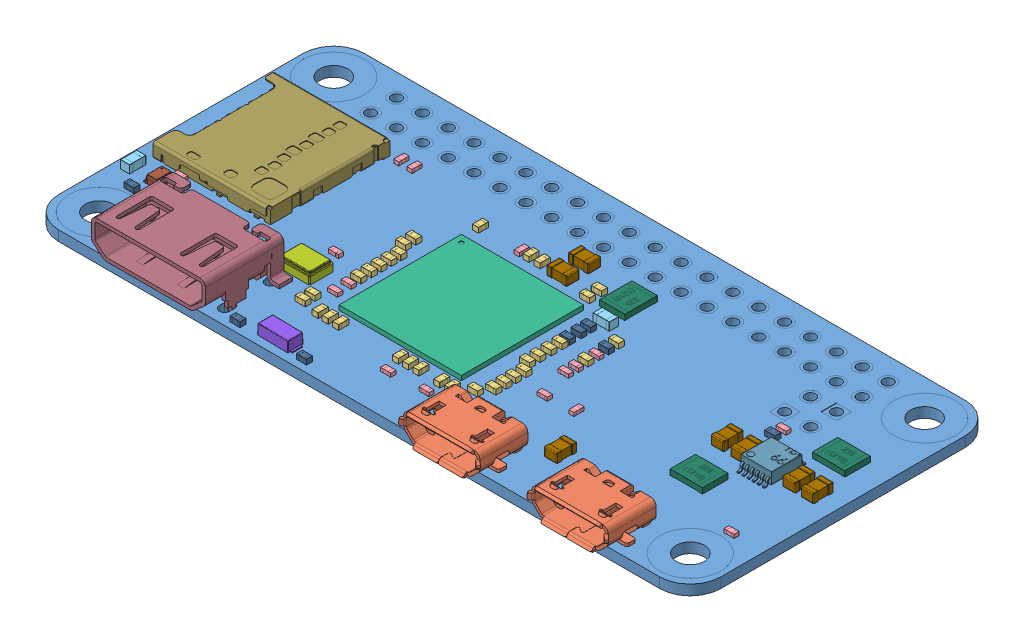
SolidWorks assembly RapberryPiZero, configuration Default. Lengths in mm.
Overall size (65 4.45 31.23).
81 component instances, 15 part files, 154 mates.
Components (placement in the parent):
- Raspberry_pizero_PCB-1: Raspberry_pizero_PCB [Default] at (-51.2564 20.0966 13.0542) size (65 1 30)
- Micro USB_input_female (short)-SMT-1: Micro USB_input_female (short)-SMT [Default] at (-42.3564 22.3216 26.5042) size (7.98 2.94 5.43)
- Micro USB_input_female (short)-SMT-2: Micro USB_input_female (short)-SMT [Default] at (-29.7564 22.3216 26.5042) size (7.98 2.94 5.43)
- 0204 - Capacitor-1: 0204 - Capacitor [Default] at (-62.4121 21.3466 11.2398) size (1 0.5 0.6)
- 0204 - Capacitor-2: 0204 - Capacitor [Default] at (-62.4121 21.3466 12.2528) size (1 0.5 0.6)
- 0204 - Capacitor-3: 0204 - Capacitor [Default] at (-61.8122 21.3466 13.3136) size (1 0.5 0.6)
- 0204 - Capacitor-4: 0204 - Capacitor [Default] at (-61.8122 21.3466 14.2646) size (1 0.5 0.6)
- 0204 - Capacitor-5: 0204 - Capacitor [Default] at (-61.8122 21.3466 15.241) size (1 0.5 0.6)
- 0204 - Capacitor-6: 0204 - Capacitor [Default] at (-61.8122 21.3466 16.2144) size (1 0.5 0.6)
- 0204 - Capacitor-7: 0204 - Capacitor [Default] at (-61.8122 21.3466 17.2416) size (1 0.5 0.6)
- 0204 - Capacitor-8: 0204 - Capacitor [Default] at (-62.5919 21.3466 20.9695) size (1 0.5 0.6)
- 0204 - Capacitor-9: 0204 - Capacitor [Default] at (-62.5919 21.3466 21.919) size (1 0.5 0.6)
- 0204 - Capacitor-10: 0204 - Capacitor [Default] at (-60.4584 21.3466 22.3712) x (0 0 1) z (-1 0 0) size (1 0.5 0.6)
- 0204 - Capacitor-11: 0204 - Capacitor [Default] at (-60.0807 21.3466 22.3712) x (0 0 -1) z (1 0 0) size (1 0.5 0.6)
- 0204 - Capacitor-12: 0204 - Capacitor [Default] at (-59.0466 21.3466 22.3712) x (0 0 -1) z (1 0 0) size (1 0.5 0.6)
- 0204 - Capacitor-13: 0204 - Capacitor [Default] at (-52.6496 21.3466 22.316) x (0 0 1) z (-1 0 0) size (1 0.5 0.6)
- 0204 - Capacitor-14: 0204 - Capacitor [Default] at (-52.25 21.3466 22.316) x (0 0 -1) z (1 0 0) size (1 0.5 0.6)
- 0204 - Capacitor-15: 0204 - Capacitor [Default] at (-51.2398 21.3466 22.316) x (0 0 -1) z (1 0 0) size (1 0.5 0.6)
- 0204 - Capacitor-16: 0204 - Capacitor [Default] at (-49.1841 21.3466 22.316) x (0 0 -1) z (1 0 0) size (1 0.5 0.6)
- 0204 - Capacitor-17: 0204 - Capacitor [Default] at (-48.1448 21.3466 22.316) x (0 0 -1) z (1 0 0) size (1 0.5 0.6)
- 0204 - Capacitor-18: 0204 - Capacitor [Default] at (-46.475 21.3466 21.113) size (1 0.5 0.6)
- 0204 - Capacitor-19: 0204 - Capacitor [Default] at (-45.7322 21.3466 20.0663) size (1 0.5 0.6)
- 0204 - Capacitor-20: 0204 - Capacitor [Default] at (-45.7322 21.3466 19.0675) size (1 0.5 0.6)
- 0204 - Capacitor-21: 0204 - Capacitor [Default] at (-45.7322 21.3466 18.1249) size (1 0.5 0.6)
- 0204 - Capacitor-22: 0204 - Capacitor [Default] at (-45.7322 21.3466 17.1095) size (1 0.5 0.6)
- 0204 - Capacitor-23: 0204 - Capacitor [Default] at (-46.3457 21.3466 16.1412) size (1 0.5 0.6)
- 0204 - Capacitor-24: 0204 - Capacitor [Default] at (-46.3457 21.3466 15.1229) size (1 0.5 0.6)
- 0204 - Capacitor-25: 0204 - Capacitor [Default] at (-46.3457 21.3466 14.0197) size (1 0.5 0.6)
- 0204 - Capacitor-26: 0204 - Capacitor [Default] at (-46.3457 21.3466 12.9589) size (1 0.5 0.6)
- 0204 - Capacitor-27: 0204 - Capacitor [Default] at (-43.6156 21.3466 13.1418) size (1 0.5 0.6)
- 0204 - Capacitor-28: 0204 - Capacitor [Default] at (-43.6156 21.3466 10.1424) size (1 0.5 0.6)
- 0204 - Capacitor-29: 0204 - Capacitor [Default] at (-48.9117 21.3466 7.6917) size (1 0.5 0.6)
- 0204 - Capacitor-30: 0204 - Capacitor [Default] at (-55.4926 21.3466 7.2526) x (0 0 -1) z (1 0 0) size (1 0.5 0.6)
- 0204 - Capacitor-31: 0204 - Capacitor [Default] at (-53.7932 21.3466 7.2526) x (0 0 1) z (-1 0 0) size (1 0.5 0.6)
- 0204 - Capacitor-32: 0204 - Capacitor [Default] at (-59.8477 21.3466 7.2526) x (0 0 1) z (-1 0 0) size (1 0.5 0.6)
- 0204- Resistor-15: 0204- Resistor [Default] at (-43.6109 21.4522 15.4193) x (-1 0 0) z (0 -1 0) size (0.99 0.51 0.36)
- 0204- Resistor-14: 0204- Resistor [Default] at (-43.6109 21.4522 14.4127) x (-1 0 0) z (0 -1 0) size (0.99 0.51 0.36)
- 0204- Resistor-13: 0204- Resistor [Default] at (-43.6109 21.4522 12.4047) x (-1 0 0) z (0 -1 0) size (0.99 0.51 0.36)
- 0204- Resistor-4: 0204- Resistor [Default] at (-42.6936 21.4522 18.4076) x (-1 0 0) z (0 -1 0) size (0.99 0.51 0.36)
- 0204- Resistor-5: 0204- Resistor [Default] at (-39.831 21.4522 18.1462) x (0 0 1) z (0 -1 0) size (0.99 0.51 0.36)
- 0204- Resistor-7: 0204- Resistor [Default] at (-61.8169 21.4522 19.8533) x (-1 0 0) z (0 -1 0) size (0.99 0.51 0.36)
- 0204- Resistor-8: 0204- Resistor [Default] at (-61.8169 21.4522 18.5178) x (-1 0 0) z (0 -1 0) size (0.99 0.51 0.36)
- 0204- Resistor-9: 0204- Resistor [Default] at (-79.148 21.4522 17.7279) x (-1 0 0) z (0 -1 0) size (0.99 0.51 0.36)
- 0204- Resistor-10: 0204- Resistor [Default] at (-56.0985 21.4522 7.2479) x (0 0 -1) z (0 -1 0) size (0.99 0.51 0.36)
- 0204- Resistor-11: 0204- Resistor [Default] at (-28.0827 21.4522 9.5819) x (-1 0 0) z (0 -1 0) size (0.99 0.51 0.36)
- 0204- Resistor-12: 0204- Resistor [Default] at (-21.8613 21.4522 20.9026) x (-1 0 0) z (0 -1 0) size (0.99 0.51 0.36)
- CAP-0306-1: CAP-0306 [Default] at (-45.8903 21.4966 8.7634) size (1.6 0.8 0.9)
- CAP-0306-2: CAP-0306 [Default] at (-82.0031 21.4966 19.0464) x (0 0 1) z (-1 0 0) size (1.6 0.8 0.9)
- Raspberry_pizero_BCM2835 with VC4-2: Raspberry_pizero_BCM2835 with VC4 [Default] at (-54.1608 21.5466 15.1238) x (1 0 0) z (0 0 -1) size (12 0.65 12)
- Crystal 3.4x2.4mm-1: Crystal 3.4x2.4mm [Default] at (-65.3089 21.0966 19.2633) size (3.2 1 2.4)
- 0204- Resistor-16: 0204- Resistor [Default] at (-68.4329 21.4522 5.4384) x (0 0 1) z (0 -1 0) size (0.99 0.51 0.36)
- 0204- Resistor-17: 0204- Resistor [Default] at (-69.7255 21.4522 5.4384) x (0 0 1) z (0 -1 0) size (0.99 0.51 0.36)
- 0204- Resistor-18: 0204- Resistor [Default] at (-65.0626 21.4522 16.5355) x (1 0 0) z (0 -1 0) size (0.99 0.51 0.36)
- 32,768 Khz Crystal-1: 32,768 Khz Crystal [Default] at (-60.5154 21.1428 26.5473) x (0.999848 -0.017452 0) z (0 0 1) size (3.4 1.03 1.5)
- 0805- Capacitor-1: 0805- Capacitor [Default] at (-51.9496 21.9966 5.2384) x (1 0 0) z (0 -1 0) size (2 1.25 0.9)
- 0805- Capacitor-2: 0805- Capacitor [Default] at (-51.9496 21.9966 7.3589) x (1 0 0) z (0 -1 0) size (2 1.25 0.9)
- 0805- Capacitor-3: 0805- Capacitor [Default] at (-37.009 21.9966 22.5384) x (0 0 -1) z (0 -1 0) size (2 1.25 0.9)
- 0805- Capacitor-4: 0805- Capacitor [Default] at (-29.8247 21.9966 13.3538) x (0 0 1) z (0 -1 0) size (2 1.25 0.9)
- 0805- Capacitor-5: 0805- Capacitor [Default] at (-27.9052 21.9966 13.3538) x (0 0 -1) z (0 -1 0) size (2 1.25 0.9)
- 0805- Capacitor-6: 0805- Capacitor [Default] at (-22.8003 21.9966 13.3538) x (0 0 -1) z (0 -1 0) size (2 1.25 0.9)
- 0805- Capacitor-7: 0805- Capacitor [Default] at (-20.9924 21.9966 13.3538) x (0 0 -1) z (0 -1 0) size (2 1.25 0.9)
- 0204- Resistor-19: 0204- Resistor [Default] at (-48.8769 21.4522 23.8207) x (1 0 0) z (0 -1 0) size (0.99 0.51 0.36)
- 0204- Resistor-20: 0204- Resistor [Default] at (-52.4165 21.4522 24.0419) x (1 0 0) z (0 -1 0) size (0.99 0.51 0.36)
- 0204 - Capacitor-33: 0204 - Capacitor [Default] at (-47.1199 21.3466 23.926) x (0 0 1) z (-1 0 0) size (1 0.5 0.6)
- 0204 - Capacitor Brown-34: 0204 - Capacitor Brown [Default] at (-57.5817 21.3466 26.803) size (1 0.5 0.6)
- 0204 - Capacitor Brown-35: 0204 - Capacitor Brown [Default] at (-64.0312 21.3466 26.8794) size (1 0.5 0.6)
- 0204 - Capacitor Brown-36: 0204 - Capacitor Brown [Default] at (-46.3457 21.3466 12.214) size (1 0.5 0.6)
- 0204 - Capacitor Brown-37: 0204 - Capacitor Brown [Default] at (-46.3457 21.3466 11.0963) size (1 0.5 0.6)
- 0204 - Capacitor Brown-38: 0204 - Capacitor Brown [Default] at (-46.3457 21.3466 10.1566) size (1 0.5 0.6)
- 0204 - Capacitor Brown-39: 0204 - Capacitor Brown [Default] at (-43.6156 21.3466 11.1151) size (1 0.5 0.6)
- 0204 - Capacitor Brown-40: 0204 - Capacitor Brown [Default] at (-28.0874 21.3466 10.3236) size (1 0.5 0.6)
- 0204 - Capacitor Brown-41: 0204 - Capacitor Brown [Default] at (-80.6197 21.3466 20.6997) size (1 0.5 0.6)
- 0204- Resistor-21: 0204- Resistor [Default] at (-78.9105 21.4522 21.1554) x (1 0 0) z (0 -1 0) size (0.99 0.51 0.36)
- 6-Pin SOT-1: 6-Pin SOT [Default] at (-79.714 21.0966 19.2138) x (0 0 1) z (0 1 0) size (1.5 1.84 0.95)
- micro sd molex-1: micro sd molex [Default] at (-74.7768 21.6766 -33.0961) x (0 0 1) z (0 1 0) size (11.95 11.4 1.45)
- hdmi type C-1: hdmi type C [Default] at (-71.3564 22.9466 28.6542) size (12.9 4.05 7.7)
- Voltage Regulator 3x3mm 12-Pin-1: Voltage Regulator 3x3mm 12-Pin [Default] at (-23.6842 21.0966 12.6105) x (1 0 0) z (0 1 0) size (3 4.1 1.2)
- 1210 inductor-1: 1210 inductor [Default] at (-46.4963 21.0916 6.3909) x (0 0 1) z (0 1 0) size (3.26 2.86 0.75)
- 1210 inductor-2: 1210 inductor [Default] at (-22.7405 21.0916 9.2394) x (1 0 0) z (0 1 0) size (3.26 2.86 0.75)
- 1210 inductor-3: 1210 inductor [Default] at (-28.2854 21.0916 17.6682) x (1 0 0) z (0 1 0) size (3.26 2.86 0.75)
- 0204 - Capacitor-34: 0204 - Capacitor [Default] at (-48.9117 21.3466 6.5273) size (1 0.5 0.6)
Mates (geometry in assembly coordinates):
- Coincident1: coincident anti-aligned: plane of Raspberry_pizero_PCB-1 through (-80.7564 21.0966 1.0542) normal (0 1 0); plane of Micro USB_input_female (short)-SMT-1 through (-46.4124 21.0966 24.1966) normal (0 -1 0)
- Coincident2: coincident anti-aligned: plane of Raspberry_pizero_PCB-1 through (-80.7564 21.0966 1.0542) normal (0 1 0); plane of Micro USB_input_female (short)-SMT-2 through (-33.8124 21.0966 24.1966) normal (0 -1 0)
- Coincident3: coincident aligned: plane of 0204 - Capacitor-13 through (-52.9516 21.5916 22.316) normal (0 1 0); plane of 0204 - Capacitor-14 through (-51.948 21.5916 22.316) normal (0 1 0)
- Coincident4: coincident aligned: plane of 0204 - Capacitor-14 through (-51.948 21.5916 22.316) normal (0 1 0); plane of 0204 - Capacitor-15 through (-50.9378 21.5916 22.316) normal (0 1 0)
- Coincident5: coincident aligned: plane of 0204 - Capacitor-15 through (-50.9378 21.5916 22.316) normal (0 1 0); plane of 0204 - Capacitor-16 through (-48.8821 21.5916 22.316) normal (0 1 0)
- Coincident6: coincident aligned: plane of 0204 - Capacitor-16 through (-48.8821 21.5916 22.316) normal (0 1 0); plane of 0204 - Capacitor-17 through (-47.8428 21.5916 22.316) normal (0 1 0)
- Coincident7: coincident aligned: plane of 0204 - Capacitor-17 through (-47.8428 21.5916 22.316) normal (0 1 0); plane of 0204 - Capacitor-18 through (-46.475 21.5916 21.415) normal (0 1 0)
- Coincident8: coincident aligned: plane of 0204 - Capacitor-18 through (-46.475 21.5916 21.415) normal (0 1 0); plane of 0204 - Capacitor-19 through (-45.7322 21.5916 20.3683) normal (0 1 0)
- Coincident9: coincident aligned: plane of 0204 - Capacitor-19 through (-45.7322 21.5916 20.3683) normal (0 1 0); plane of 0204 - Capacitor-20 through (-45.7322 21.5916 19.3695) normal (0 1 0)
- Coincident10: coincident aligned: plane of 0204 - Capacitor-20 through (-45.7322 21.5916 19.3695) normal (0 1 0); plane of 0204 - Capacitor-21 through (-45.7322 21.5916 18.4269) normal (0 1 0)
- Coincident11: coincident aligned: plane of 0204 - Capacitor-21 through (-45.7322 21.5916 18.4269) normal (0 1 0); plane of 0204 - Capacitor-22 through (-45.7322 21.5916 17.4115) normal (0 1 0)
- Coincident12: coincident aligned: plane of 0204 - Capacitor-22 through (-45.7322 21.5916 17.4115) normal (0 1 0); plane of 0204 - Capacitor-23 through (-46.3457 21.5916 16.4432) normal (0 1 0)
- Coincident13: coincident aligned: plane of 0204 - Capacitor-23 through (-46.3457 21.5916 16.4432) normal (0 1 0); plane of 0204 - Capacitor-24 through (-46.3457 21.5916 15.4249) normal (0 1 0)
- Coincident14: coincident aligned: plane of 0204 - Capacitor-24 through (-46.3457 21.5916 15.4249) normal (0 1 0); plane of 0204 - Capacitor-25 through (-46.3457 21.5916 14.3217) normal (0 1 0)
- Coincident15: coincident aligned: plane of 0204 - Capacitor-25 through (-46.3457 21.5916 14.3217) normal (0 1 0); plane of 0204 - Capacitor-26 through (-46.3457 21.5916 13.2609) normal (0 1 0)
- Coincident16: coincident aligned: plane of 0204 - Capacitor-26 through (-46.3457 21.5916 13.2609) normal (0 1 0); plane of 0204 - Capacitor-27 through (-43.6156 21.5916 13.4438) normal (0 1 0)
- Coincident17: coincident aligned: plane of 0204 - Capacitor-27 through (-43.6156 21.5916 13.4438) normal (0 1 0); plane of 0204 - Capacitor-28 through (-43.6156 21.5916 10.4444) normal (0 1 0)
- Coincident18: coincident aligned: plane of 0204 - Capacitor-28 through (-43.6156 21.5916 10.4444) normal (0 1 0); plane of 0204 - Capacitor-29 through (-48.9117 21.5916 7.9937) normal (0 1 0)
- Coincident19: coincident aligned: plane of 0204 - Capacitor-29 through (-48.9117 21.5916 7.9937) normal (0 1 0); plane of 0204 - Capacitor-31 through (-54.0952 21.5916 7.2526) normal (0 1 0)
- Coincident20: coincident aligned: plane of 0204 - Capacitor-30 through (-55.1906 21.5916 7.2526) normal (0 1 0); plane of 0204 - Capacitor-31 through (-54.0952 21.5916 7.2526) normal (0 1 0)
- Coincident21: coincident aligned: plane of 0204 - Capacitor-30 through (-55.1906 21.5916 7.2526) normal (0 1 0); plane of 0204 - Capacitor-32 through (-60.1497 21.5916 7.2526) normal (0 1 0)
- Coincident22: coincident aligned: plane of 0204 - Capacitor-1 through (-62.4121 21.5916 11.5418) normal (0 1 0); plane of 0204 - Capacitor-32 through (-60.1497 21.5916 7.2526) normal (0 1 0)
- Coincident23: coincident aligned: plane of 0204 - Capacitor-1 through (-62.4121 21.5916 11.5418) normal (0 1 0); plane of 0204 - Capacitor-2 through (-62.4121 21.5916 12.5548) normal (0 1 0)
- Coincident24: coincident aligned: plane of 0204 - Capacitor-2 through (-62.4121 21.5916 12.5548) normal (0 1 0); plane of 0204 - Capacitor-3 through (-61.8122 21.5916 13.6156) normal (0 1 0)
- Coincident25: coincident aligned: plane of 0204 - Capacitor-3 through (-61.8122 21.5916 13.6156) normal (0 1 0); plane of 0204 - Capacitor-4 through (-61.8122 21.5916 14.5666) normal (0 1 0)
- Coincident26: coincident aligned: plane of 0204 - Capacitor-4 through (-61.8122 21.5916 14.5666) normal (0 1 0); plane of 0204 - Capacitor-5 through (-61.8122 21.5916 15.543) normal (0 1 0)
- Coincident27: coincident aligned: plane of 0204 - Capacitor-5 through (-61.8122 21.5916 15.543) normal (0 1 0); plane of 0204 - Capacitor-6 through (-61.8122 21.5916 16.5164) normal (0 1 0)
- Coincident28: coincident aligned: plane of 0204 - Capacitor-6 through (-61.8122 21.5916 16.5164) normal (0 1 0); plane of 0204 - Capacitor-7 through (-61.8122 21.5916 17.5436) normal (0 1 0)
- Coincident29: coincident aligned: plane of 0204 - Capacitor-7 through (-61.8122 21.5916 17.5436) normal (0 1 0); plane of 0204 - Capacitor-8 through (-62.5919 21.5916 21.2715) normal (0 1 0)
- Coincident30: coincident aligned: plane of 0204 - Capacitor-8 through (-62.5919 21.5916 21.2715) normal (0 1 0); plane of 0204 - Capacitor-9 through (-62.5919 21.5916 22.221) normal (0 1 0)
- Coincident31: coincident aligned: plane of 0204 - Capacitor-9 through (-62.5919 21.5916 22.221) normal (0 1 0); plane of 0204 - Capacitor-10 through (-60.7604 21.5916 22.3712) normal (0 1 0)
- Coincident32: coincident aligned: plane of 0204 - Capacitor-10 through (-60.7604 21.5916 22.3712) normal (0 1 0); plane of 0204 - Capacitor-11 through (-59.7787 21.5916 22.3712) normal (0 1 0)
- Coincident33: coincident aligned: plane of 0204 - Capacitor-11 through (-59.7787 21.5916 22.3712) normal (0 1 0); plane of 0204 - Capacitor-12 through (-58.7446 21.5916 22.3712) normal (0 1 0)
- Coincident34: coincident anti-aligned: plane of Raspberry_pizero_PCB-1 through (-80.7564 21.0966 1.0542) normal (0 1 0); plane of 0204 - Capacitor-9 through (-62.9669 21.0966 22.219) normal (0 -1 0)
- Coincident35: coincident aligned: plane of 0204 - Capacitor-25 through (-46.8457 21.0966 14.3197) normal (-1 0 0); plane of 0204 - Capacitor-26 through (-46.8457 21.0966 13.2589) normal (-1 0 0)
- Coincident36: coincident aligned: plane of 0204 - Capacitor-24 through (-46.8457 21.0966 15.4229) normal (-1 0 0); plane of 0204 - Capacitor-25 through (-46.8457 21.0966 14.3197) normal (-1 0 0)
- Coincident37: coincident aligned: plane of 0204 - Capacitor-23 through (-46.8457 21.0966 16.4412) normal (-1 0 0); plane of 0204 - Capacitor-24 through (-46.8457 21.0966 15.4229) normal (-1 0 0)
- Coincident38: coincident aligned: plane of 0204 - Capacitor-27 through (-44.1156 21.0966 13.4418) normal (-1 0 0); plane of 0204 - Capacitor-28 through (-44.1156 21.0966 10.4424) normal (-1 0 0)
- Parallel1: parallel anti-aligned: plane of Raspberry_pizero_PCB-1 through (-80.7564 21.0966 -1.9458) normal (0 0 -1); plane of 0204 - Capacitor-30 through (-55.1926 21.0966 7.7526) normal (0 0 1)
- Coincident39: coincident aligned: plane of 0204 - Capacitor-30 through (-55.1926 21.0966 6.7526) normal (0 0 -1); plane of 0204 - Capacitor-31 through (-54.0932 21.0966 6.7526) normal (0 0 -1)
- Coincident40: coincident aligned: plane of 0204 - Capacitor-30 through (-55.1926 21.0966 6.7526) normal (0 0 -1); plane of 0204 - Capacitor-32 through (-60.1477 21.0966 6.7526) normal (0 0 -1)
- Coincident41: coincident aligned: plane of 0204 - Capacitor-1 through (-62.9121 21.0966 11.5398) normal (-1 0 0); plane of 0204 - Capacitor-2 through (-62.9121 21.0966 12.5528) normal (-1 0 0)
- Coincident42: coincident aligned: plane of 0204 - Capacitor-3 through (-62.3122 21.0966 13.6136) normal (-1 0 0); plane of 0204 - Capacitor-4 through (-62.3122 21.0966 14.5646) normal (-1 0 0)
- Coincident43: coincident aligned: plane of 0204 - Capacitor-4 through (-62.3122 21.0966 14.5646) normal (-1 0 0); plane of 0204 - Capacitor-5 through (-62.3122 21.0966 15.541) normal (-1 0 0)
- Coincident44: coincident aligned: plane of 0204 - Capacitor-5 through (-62.3122 21.0966 15.541) normal (-1 0 0); plane of 0204 - Capacitor-6 through (-62.3122 21.0966 16.5144) normal (-1 0 0)
- Coincident45: coincident aligned: plane of 0204 - Capacitor-6 through (-62.3122 21.0966 16.5144) normal (-1 0 0); plane of 0204 - Capacitor-7 through (-62.3122 21.0966 17.5416) normal (-1 0 0)
- Coincident46: coincident aligned: plane of 0204 - Capacitor-8 through (-63.0919 21.0966 21.2695) normal (-1 0 0); plane of 0204 - Capacitor-9 through (-63.0919 21.0966 22.219) normal (-1 0 0)
- Parallel2: parallel anti-aligned: plane of Raspberry_pizero_PCB-1 through (-80.7564 21.0966 28.0542) normal (0 0 1); plane of 0204 - Capacitor-10 through (-60.7584 21.0966 21.8712) normal (0 0 -1)
- Coincident48: coincident aligned: plane of 0204 - Capacitor-10 through (-60.7584 21.0966 22.8712) normal (0 0 1); plane of 0204 - Capacitor-11 through (-59.7807 21.0966 22.8712) normal (0 0 1)
- Coincident49: coincident aligned: plane of 0204 - Capacitor-11 through (-59.7807 21.0966 22.8712) normal (0 0 1); plane of 0204 - Capacitor-12 through (-58.7466 21.0966 22.8712) normal (0 0 1)
- Parallel3: parallel anti-aligned: plane of Raspberry_pizero_PCB-1 through (-80.7564 21.0966 28.0542) normal (0 0 1); plane of 0204 - Capacitor-13 through (-52.9496 21.0966 21.816) normal (0 0 -1)
- Coincident51: coincident aligned: plane of 0204 - Capacitor-13 through (-52.9496 21.0966 22.816) normal (0 0 1); plane of 0204 - Capacitor-14 through (-51.95 21.0966 22.816) normal (0 0 1)
- Coincident52: coincident aligned: plane of 0204 - Capacitor-14 through (-51.95 21.0966 22.816) normal (0 0 1); plane of 0204 - Capacitor-15 through (-50.9398 21.0966 22.816) normal (0 0 1)
- Coincident53: coincident aligned: plane of 0204 - Capacitor-15 through (-50.9398 21.0966 22.816) normal (0 0 1); plane of 0204 - Capacitor-16 through (-48.8841 21.0966 22.816) normal (0 0 1)
- Coincident54: coincident aligned: plane of 0204 - Capacitor-16 through (-48.8841 21.0966 22.816) normal (0 0 1); plane of 0204 - Capacitor-17 through (-47.8448 21.0966 22.816) normal (0 0 1)
- Parallel7: parallel anti-aligned: plane of Raspberry_pizero_PCB-1 through (-80.7564 21.0966 28.0542) normal (0 0 1); plane of CAP-0306-2 through (-82.4531 21.0966 18.2464) normal (0 0 -1)
- Parallel8: parallel aligned: plane of Raspberry_pizero_PCB-1 through (-18.7564 21.0966 25.0542) normal (1 0 0); plane of CAP-0306-1 through (-45.0903 21.0966 9.2134) normal (1 0 0)
- Coincident77: coincident aligned: plane of 0204 - Capacitor-21 through (-46.2322 21.0966 18.4249) normal (-1 0 0); plane of 0204 - Capacitor-22 through (-46.2322 21.0966 17.4095) normal (-1 0 0)
- Coincident78: coincident aligned: plane of 0204 - Capacitor-20 through (-46.2322 21.0966 19.3675) normal (-1 0 0); plane of 0204 - Capacitor-21 through (-46.2322 21.0966 18.4249) normal (-1 0 0)
- Coincident79: coincident aligned: plane of 0204 - Capacitor-19 through (-46.2322 21.0966 20.3663) normal (-1 0 0); plane of 0204 - Capacitor-20 through (-46.2322 21.0966 19.3675) normal (-1 0 0)
- Coincident80: coincident aligned: plane of Micro USB_input_female (short)-SMT-1 through (-39.2364 21.3596 23.1542) normal (0 0 -1); plane of Micro USB_input_female (short)-SMT-2 through (-26.6364 21.3596 23.1542) normal (0 0 -1)
- Distance1: distance = 41.4 mm: moEndPointRef_w of Micro USB_input_female (short)-SMT-1; plane of Raspberry_pizero_PCB-1 through (-83.7564 21.0966 25.0542) normal (-1 0 0)
- Distance3: distance = 0.8 mm aligned: plane of Micro USB_input_female (short)-SMT-1 through (-46.2564 21.0476 28.8542) normal (0 0 1); plane of Raspberry_pizero_PCB-1 through (-80.7564 21.0966 28.0542) normal (0 0 1)
- Distance4: distance = 54 mm: moEndPointRef_w of Micro USB_input_female (short)-SMT-2; plane of Raspberry_pizero_PCB-1 through (-83.7564 21.0966 25.0542) normal (-1 0 0)
- Coincident86: coincident anti-aligned: plane of Raspberry_pizero_PCB-1 through (-80.7564 21.0966 1.0542) normal (0 1 0); plane of Raspberry_pizero_BCM2835 with VC4-2 through (-54.1608 21.0966 15.1238) normal (0 -1 0)
- Parallel10: parallel anti-aligned: plane of Raspberry_pizero_BCM2835 with VC4-2 through (-60.1608 21.0966 9.1238) normal (0 0 -1); plane of Raspberry_pizero_PCB-1 through (-80.7564 21.0966 28.0542) normal (0 0 1)
- Coincident88: coincident anti-aligned: plane of Raspberry_pizero_PCB-1 through (-80.7564 21.0966 1.0542) normal (0 1 0); plane of CAP-0306-1 through (-45.2653 21.0966 9.2134) normal (0 -1 0)
- Coincident89: coincident aligned: plane of 0204- Resistor-7 through (-61.5248 21.0966 19.5993) normal (0 -1 0); plane of 0204- Resistor-8 through (-61.5248 21.0966 18.2638) normal (0 -1 0)
- Coincident90: coincident anti-aligned: plane of Raspberry_pizero_PCB-1 through (-80.7564 21.0966 1.0542) normal (0 1 0); plane of 0204- Resistor-8 through (-61.5248 21.0966 18.2638) normal (0 -1 0)
- Parallel11: parallel aligned: plane of Raspberry_pizero_PCB-1 through (-80.7564 21.0966 28.0542) normal (0 0 1); plane of 0204 - Capacitor-7 through (-61.8122 21.1016 17.8406) normal (0 0 1)
- Coincident92: coincident aligned: plane of 0204 - Capacitor-7 through (-62.3122 21.0966 17.5416) normal (-1 0 0); plane of 0204- Resistor-8 through (-62.3122 21.0966 18.2638) normal (-1 0 0)
- Coincident93: coincident aligned: plane of 0204- Resistor-7 through (-62.3122 21.0966 19.5993) normal (-1 0 0); plane of 0204- Resistor-8 through (-62.3122 21.0966 18.2638) normal (-1 0 0)
- Coincident94: coincident aligned: plane of 0204 - Capacitor-30 through (-55.1926 21.0966 6.7526) normal (0 0 -1); plane of 0204- Resistor-10 through (-55.8445 21.0966 6.7526) normal (0 0 -1)
- Coincident95: coincident anti-aligned: plane of Raspberry_pizero_PCB-1 through (-80.7564 21.0966 1.0542) normal (0 1 0); plane of 0204- Resistor-10 through (-55.8445 21.0966 6.9558) normal (0 -1 0)
- Coincident96: coincident aligned: plane of 0204- Resistor-14 through (-43.903 21.0966 14.1587) normal (0 -1 0); plane of 0204- Resistor-13 through (-43.903 21.0966 12.1507) normal (0 -1 0)
- Coincident97: coincident aligned: plane of 0204- Resistor-15 through (-43.903 21.0966 15.1653) normal (0 -1 0); plane of 0204- Resistor-14 through (-43.903 21.0966 14.1587) normal (0 -1 0)
- Coincident98: coincident aligned: plane of 0204- Resistor-15 through (-43.903 21.0966 15.1653) normal (0 -1 0); plane of 0204- Resistor-4 through (-42.9857 21.0966 18.1536) normal (0 -1 0)
- Coincident99: coincident anti-aligned: plane of Raspberry_pizero_PCB-1 through (-80.7564 21.0966 1.0542) normal (0 1 0); plane of 0204- Resistor-15 through (-43.903 21.0966 15.1653) normal (0 -1 0)
- Coincident101: coincident aligned: plane of 0204- Resistor-5 through (-40.085 21.0966 18.4383) normal (0 -1 0); plane of 0204- Resistor-11 through (-27.7906 21.0966 9.3279) normal (0 -1 0)
- Coincident102: coincident aligned: plane of 0204- Resistor-11 through (-27.7906 21.0966 9.3279) normal (0 -1 0); plane of 0204- Resistor-12 through (-21.5692 21.0966 20.6486) normal (0 -1 0)
- Coincident103: coincident anti-aligned: plane of Raspberry_pizero_PCB-1 through (-80.7564 21.0966 1.0542) normal (0 1 0); plane of Crystal 3.4x2.4mm-1 through (-65.3089 21.0966 19.2633) normal (0 -1 0)
- Parallel12: parallel aligned: plane of Raspberry_pizero_PCB-1 through (-80.7564 21.0966 28.0542) normal (0 0 1); plane of Crystal 3.4x2.4mm-1 through (-66.9089 21.7966 20.4633) normal (0 0 1)
- Coincident104: coincident anti-aligned: plane of Raspberry_pizero_PCB-1 through (-80.7564 21.0966 1.0542) normal (0 1 0); plane of 0204- Resistor-9 through (-78.8559 21.0966 17.4739) normal (0 -1 0)
- Parallel13: parallel aligned: plane of Raspberry_pizero_PCB-1 through (-80.7564 21.0966 28.0542) normal (0 0 1); plane of 0204- Resistor-9 through (-78.2985 21.4532 17.9829) normal (0 0 1)
- Coincident105: coincident anti-aligned: plane of Raspberry_pizero_PCB-1 through (-80.7564 21.0966 1.0542) normal (0 1 0); plane of CAP-0306-2 through (-82.4531 21.0966 19.6714) normal (0 -1 0)
- Coincident106: coincident aligned: plane of 0204 - Capacitor-28 through (-43.1156 21.0966 10.4424) normal (1 0 0); plane of 0204- Resistor-13 through (-43.1156 21.0966 12.1507) normal (1 0 0)
- Coincident107: coincident aligned: plane of 0204 - Capacitor-27 through (-43.1156 21.0966 13.4418) normal (1 0 0); plane of 0204- Resistor-14 through (-43.1156 21.0966 14.1587) normal (1 0 0)
- Parallel14: parallel aligned: plane of Raspberry_pizero_PCB-1 through (-80.7564 21.0966 28.0542) normal (0 0 1); plane of 0204- Resistor-14 through (-42.7614 21.4532 14.6677) normal (0 0 1)
- Coincident110: coincident aligned: plane of 0204- Resistor-15 through (-43.1156 21.0966 15.1653) normal (1 0 0); plane of 0204- Resistor-14 through (-43.1156 21.0966 14.1587) normal (1 0 0)
- Parallel15: parallel aligned: plane of 0204- Resistor-15 through (-43.1156 21.0966 15.1653) normal (1 0 0); plane of 0204- Resistor-4 through (-42.1983 21.0966 18.1536) normal (1 0 0)
- Parallel16: parallel aligned: plane of Raspberry_pizero_PCB-1 through (-80.7564 21.0966 28.0542) normal (0 0 1); plane of 0204- Resistor-5 through (-40.085 21.0966 18.6415) normal (0 0 1)
- Coincident112: coincident anti-aligned: plane of Raspberry_pizero_PCB-1 through (-80.7564 21.0966 1.0542) normal (0 1 0); plane of 0204- Resistor-5 through (-40.085 21.0966 18.4383) normal (0 -1 0)
- Parallel17: parallel aligned: plane of Raspberry_pizero_PCB-1 through (-18.7564 21.0966 25.0542) normal (1 0 0); plane of 0204- Resistor-12 through (-21.366 21.0966 20.6486) normal (1 0 0)
- Parallel18: parallel aligned: plane of 0204- Resistor-11 through (-27.5874 21.0966 9.3279) normal (1 0 0); plane of 0204- Resistor-12 through (-21.366 21.0966 20.6486) normal (1 0 0)
- Coincident115: coincident anti-aligned: plane of Raspberry_pizero_PCB-1 through (-80.7564 21.0966 1.0542) normal (0 1 0); plane of 0204- Resistor-16 through (-68.6869 21.0966 5.1463) normal (0 -1 0)
- Coincident116: coincident aligned: plane of 0204- Resistor-16 through (-68.6879 21.4532 4.5889) normal (0 1 0); plane of 0204- Resistor-17 through (-69.9805 21.4532 4.5889) normal (0 1 0)
- Coincident117: coincident aligned: plane of 0204- Resistor-17 through (-69.9805 21.4532 4.5889) normal (0 1 0); plane of 0204- Resistor-18 through (-65.9121 21.4532 16.7905) normal (0 1 0)
- Coincident118: coincident aligned: plane of 0204- Resistor-16 through (-68.6869 21.0966 5.9337) normal (0 0 1); plane of 0204- Resistor-17 through (-69.9795 21.0966 5.9337) normal (0 0 1)
- Parallel19: parallel anti-aligned: plane of Raspberry_pizero_PCB-1 through (-80.7564 21.0966 -1.9458) normal (0 0 -1); plane of 0204- Resistor-17 through (-69.9795 21.0966 5.9337) normal (0 0 1)
- Parallel20: parallel aligned: plane of Raspberry_pizero_PCB-1 through (-80.7564 21.0966 28.0542) normal (0 0 1); plane of 0204- Resistor-18 through (-65.9121 21.4532 16.7905) normal (0 0 1)
- Coincident120: coincident anti-aligned: plane of Raspberry_pizero_PCB-1 through (-80.7564 21.0966 1.0542) normal (0 1 0); plane of 32,768 Khz Crystal-1 through (-59.5156 21.0966 27.0473) normal (0 -1 0)
- Coincident121: coincident anti-aligned: plane of Raspberry_pizero_PCB-1 through (-80.7564 21.0966 1.0542) normal (0 1 0); plane of 0805- Capacitor-1 through (-52.9496 21.0966 5.8634) normal (0 -1 0)
- Coincident122: coincident anti-aligned: plane of Raspberry_pizero_PCB-1 through (-80.7564 21.0966 1.0542) normal (0 1 0); plane of 0805- Capacitor-2 through (-52.9496 21.0966 7.9839) normal (0 -1 0)
- Coincident123: coincident anti-aligned: plane of Raspberry_pizero_PCB-1 through (-80.7564 21.0966 1.0542) normal (0 1 0); plane of 0805- Capacitor-3 through (-37.634 21.0966 21.5384) normal (0 -1 0)
- Coincident124: coincident anti-aligned: plane of Raspberry_pizero_PCB-1 through (-80.7564 21.0966 1.0542) normal (0 1 0); plane of 0805- Capacitor-4 through (-30.4497 21.0966 12.3538) normal (0 -1 0)
- Coincident125: coincident anti-aligned: plane of Raspberry_pizero_PCB-1 through (-80.7564 21.0966 1.0542) normal (0 1 0); plane of 0805- Capacitor-5 through (-27.2802 21.0966 14.3538) normal (0 -1 0)
- Parallel21: parallel anti-aligned: plane of Raspberry_pizero_PCB-1 through (-80.7564 21.0966 28.0542) normal (0 0 1); plane of 0805- Capacitor-4 through (-29.8247 21.9966 12.3538) normal (0 0 -1)
- Coincident126: coincident aligned: plane of 0805- Capacitor-4 through (-29.8247 21.9966 14.3538) normal (0 0 1); plane of 0805- Capacitor-5 through (-27.9052 21.9966 14.3538) normal (0 0 1)
- Coincident127: coincident anti-aligned: plane of Raspberry_pizero_PCB-1 through (-80.7564 21.0966 1.0542) normal (0 1 0); plane of 0805- Capacitor-6 through (-22.1753 21.0966 14.3538) normal (0 -1 0)
- Coincident128: coincident anti-aligned: plane of Raspberry_pizero_PCB-1 through (-80.7564 21.0966 1.0542) normal (0 1 0); plane of 0805- Capacitor-7 through (-20.3674 21.0966 14.3538) normal (0 -1 0)
- Coincident129: coincident aligned: plane of 0805- Capacitor-5 through (-27.9052 21.9966 14.3538) normal (0 0 1); plane of 0805- Capacitor-6 through (-22.8003 21.9966 14.3538) normal (0 0 1)
- Coincident130: coincident aligned: plane of 0805- Capacitor-6 through (-22.8003 21.9966 14.3538) normal (0 0 1); plane of 0805- Capacitor-7 through (-20.9924 21.9966 14.3538) normal (0 0 1)
- Parallel22: parallel anti-aligned: plane of Raspberry_pizero_PCB-1 through (-80.7564 21.0966 28.0542) normal (0 0 1); plane of 0805- Capacitor-3 through (-37.009 21.9966 21.5384) normal (0 0 -1)
- Coincident131: coincident aligned: plane of 0805- Capacitor-1 through (-50.9496 21.9966 5.2384) normal (1 0 0); plane of 0805- Capacitor-2 through (-50.9496 21.9966 7.3589) normal (1 0 0)
- Parallel23: parallel anti-aligned: plane of Raspberry_pizero_PCB-1 through (-80.7564 21.0966 28.0542) normal (0 0 1); plane of 6-Pin SOT-1 through (-80.214 22.0466 18.4638) normal (0 0 -1)
- Coincident134: coincident anti-aligned: plane of Raspberry_pizero_PCB-1 through (-80.7564 21.0966 1.0542) normal (0 1 0); plane of 6-Pin SOT-1 through (-80.434 21.0966 19.8263) normal (0 -1 0)
- Coincident135: coincident anti-aligned: plane of Raspberry_pizero_PCB-1 through (-80.7564 21.0966 1.0542) normal (0 1 0); plane of micro sd molex-1 through (-71.1444 21.0966 16.7043) normal (0 -1 0)
- Parallel24: parallel aligned: plane of Raspberry_pizero_PCB-1 through (-80.7564 21.0966 -1.9458) normal (0 0 -1); plane of micro sd molex-1 through (-84.5393 22.448 5.3989) normal (0 0 -1)
- Coincident141: coincident anti-aligned: plane of Raspberry_pizero_PCB-1 through (-80.7564 21.0966 1.0542) normal (0 1 0); plane of hdmi type C-1 through (-77.8064 21.0966 20.9542) normal (0 -1 0)
- Distance5: distance = 12.4 mm: moEndPointRef_w of hdmi type C-1; plane of Raspberry_pizero_PCB-1 through (-83.7564 21.0966 25.0542) normal (-1 0 0)
- Distance6: distance = 17.2 mm: moEndPointRef_w of micro sd molex-1; plane of Raspberry_pizero_PCB-1 through (-80.7564 21.0966 28.0542) normal (0 0 1)
- Parallel25: parallel aligned: plane of Raspberry_pizero_PCB-1 through (-80.7564 21.0966 28.0542) normal (0 0 1); plane of hdmi type C-1 through (-71.3564 22.9466 28.6542) normal (0 0 1)
- Distance7: distance = 0.6 mm aligned: plane of hdmi type C-1 through (-71.3564 22.9466 28.6542) normal (0 0 1); plane of Raspberry_pizero_PCB-1 through (-80.7564 21.0966 28.0542) normal (0 0 1)
- Coincident142: coincident anti-aligned: plane of Raspberry_pizero_PCB-1 through (-80.7564 21.0966 1.0542) normal (0 1 0); plane of 0204 - Capacitor Brown-34 through (-57.9567 21.0966 27.103) normal (0 -1 0)
- Coincident143: coincident aligned: plane of 0204 - Capacitor Brown-34 through (-57.5817 21.5916 27.105) normal (0 1 0); plane of 0204 - Capacitor Brown-35 through (-64.0312 21.5916 27.1814) normal (0 1 0)
- Coincident144: coincident aligned: plane of 0204 - Capacitor-18 through (-46.475 21.5916 21.415) normal (0 1 0); plane of 0204 - Capacitor-33 through (-47.4219 21.5916 23.926) normal (0 1 0)
- Parallel26: parallel anti-aligned: plane of Raspberry_pizero_PCB-1 through (-80.7564 21.0966 28.0542) normal (0 0 1); plane of 0204 - Capacitor-33 through (-47.4199 21.0966 23.426) normal (0 0 -1)
- Coincident146: coincident anti-aligned: plane of Raspberry_pizero_PCB-1 through (-80.7564 21.0966 1.0542) normal (0 1 0); plane of 0204- Resistor-19 through (-48.5848 21.0966 24.0747) normal (0 -1 0)
- Coincident147: coincident anti-aligned: plane of Raspberry_pizero_PCB-1 through (-80.7564 21.0966 1.0542) normal (0 1 0); plane of 0204- Resistor-20 through (-52.1244 21.0966 24.2959) normal (0 -1 0)
- Coincident148: coincident anti-aligned: plane of Raspberry_pizero_PCB-1 through (-80.7564 21.0966 1.0542) normal (0 1 0); plane of 0204- Resistor-21 through (-79.2026 21.0966 21.4094) normal (0 -1 0)
- Coincident149: coincident anti-aligned: plane of Raspberry_pizero_PCB-1 through (-80.7564 21.0966 1.0542) normal (0 1 0); plane of 0204 - Capacitor Brown-41 through (-80.9947 21.0966 20.9997) normal (0 -1 0)
- Parallel27: parallel aligned: plane of Raspberry_pizero_PCB-1 through (-80.7564 21.0966 28.0542) normal (0 0 1); plane of 0204- Resistor-21 through (-78.9105 21.4522 21.4094) normal (0 0 1)
- Parallel28: parallel aligned: plane of Raspberry_pizero_PCB-1 through (-80.7564 21.0966 28.0542) normal (0 0 1); plane of 0204 - Capacitor Brown-41 through (-80.6197 21.1016 21.2987) normal (0 0 1)
- Parallel29: parallel aligned: plane of 0204- Resistor-19 through (-49.7264 21.4532 24.0757) normal (0 0 1); plane of 0204- Resistor-20 through (-53.266 21.4532 24.2969) normal (0 0 1)
- Coincident152: coincident aligned: plane of 0204 - Capacitor Brown-34 through (-57.5817 21.5916 27.105) normal (0 1 0); plane of 0204 - Capacitor Brown-39 through (-43.6156 21.5916 11.4171) normal (0 1 0)
- Coincident153: coincident aligned: plane of 0204 - Capacitor Brown-36 through (-46.3457 21.5916 12.516) normal (0 1 0); plane of 0204 - Capacitor Brown-39 through (-43.6156 21.5916 11.4171) normal (0 1 0)
- Coincident154: coincident aligned: plane of 0204 - Capacitor Brown-36 through (-46.3457 21.5916 12.516) normal (0 1 0); plane of 0204 - Capacitor Brown-37 through (-46.3457 21.5916 11.3983) normal (0 1 0)
- Coincident155: coincident aligned: plane of 0204 - Capacitor Brown-37 through (-46.3457 21.5916 11.3983) normal (0 1 0); plane of 0204 - Capacitor Brown-38 through (-46.3457 21.5916 10.4586) normal (0 1 0)
- Coincident156: coincident aligned: plane of 0204 - Capacitor-26 through (-45.8457 21.0966 13.2589) normal (1 0 0); plane of 0204 - Capacitor Brown-36 through (-45.8457 21.0966 12.514) normal (1 0 0)
- Coincident157: coincident aligned: plane of 0204 - Capacitor Brown-36 through (-45.8457 21.0966 12.514) normal (1 0 0); plane of 0204 - Capacitor Brown-37 through (-45.8457 21.0966 11.3963) normal (1 0 0)
- Coincident158: coincident aligned: plane of 0204 - Capacitor Brown-37 through (-45.8457 21.0966 11.3963) normal (1 0 0); plane of 0204 - Capacitor Brown-38 through (-45.8457 21.0966 10.4566) normal (1 0 0)
- Coincident159: coincident aligned: plane of 0204 - Capacitor-28 through (-43.1156 21.0966 10.4424) normal (1 0 0); plane of 0204 - Capacitor Brown-39 through (-43.1156 21.0966 11.4151) normal (1 0 0)
- Coincident160: coincident aligned: plane of 0204 - Capacitor Brown-39 through (-43.6156 21.5916 11.4171) normal (0 1 0); plane of 0204 - Capacitor Brown-40 through (-28.0874 21.5916 10.6256) normal (0 1 0)
- Coincident161: coincident aligned: plane of 0204- Resistor-11 through (-27.5874 21.0966 9.3279) normal (1 0 0); plane of 0204 - Capacitor Brown-40 through (-27.5874 21.0966 10.6236) normal (1 0 0)
- Coincident163: coincident anti-aligned: plane of Raspberry_pizero_PCB-1 through (-80.7564 21.0966 1.0542) normal (0 1 0); plane of Voltage Regulator 3x3mm 12-Pin-1 through (-24.1342 21.0966 11.3118) normal (0 -1 0)
- Parallel30: parallel aligned: plane of Raspberry_pizero_PCB-1 through (-18.7564 21.0966 25.0542) normal (1 0 0); plane of Voltage Regulator 3x3mm 12-Pin-1 through (-23.9842 22.2966 11.8605) normal (1 0 0)
- Coincident165: coincident anti-aligned: plane of Raspberry_pizero_PCB-1 through (-80.7564 21.0966 1.0542) normal (0 1 0); line of 1210 inductor-2 through (-21.1405 21.0966 7.9944) axis (0 0 1)
- Coincident166: coincident aligned: plane of 1210 inductor-3 through (-28.2854 21.6416 16.4182) normal (0 1 0); plane of 1210 inductor-2 through (-22.7405 21.6416 7.9894) normal (0 1 0)
- Coincident167: coincident aligned: plane of 0204 - Capacitor-29 through (-48.9117 21.5916 7.9937) normal (0 1 0); plane of 0204 - Capacitor-34 through (-48.9117 21.5916 6.8293) normal (0 1 0)
- Coincident168: coincident aligned: plane of 0204 - Capacitor-29 through (-49.4117 21.0966 7.9917) normal (-1 0 0); plane of 0204 - Capacitor-34 through (-49.4117 21.0966 6.8273) normal (-1 0 0)
- Coincident169: coincident aligned: plane of 1210 inductor-1 through (-45.2463 21.6416 6.3909) normal (0 1 0); plane of 1210 inductor-2 through (-22.7405 21.6416 7.9894) normal (0 1 0)
- Parallel31: parallel aligned: plane of Raspberry_pizero_PCB-1 through (-18.7564 21.0966 25.0542) normal (1 0 0); plane of 1210 inductor-2 through (-21.1405 21.3666 10.4894) normal (1 0 0)
- Parallel32: parallel aligned: plane of Raspberry_pizero_PCB-1 through (-18.7564 21.0966 25.0542) normal (1 0 0); plane of 1210 inductor-3 through (-26.6854 21.3666 18.9182) normal (1 0 0)
- Parallel33: parallel aligned: plane of Raspberry_pizero_PCB-1 through (-18.7564 21.0966 25.0542) normal (1 0 0); plane of 1210 inductor-1 through (-45.2468 21.3666 6.3909) normal (1 0 0)
